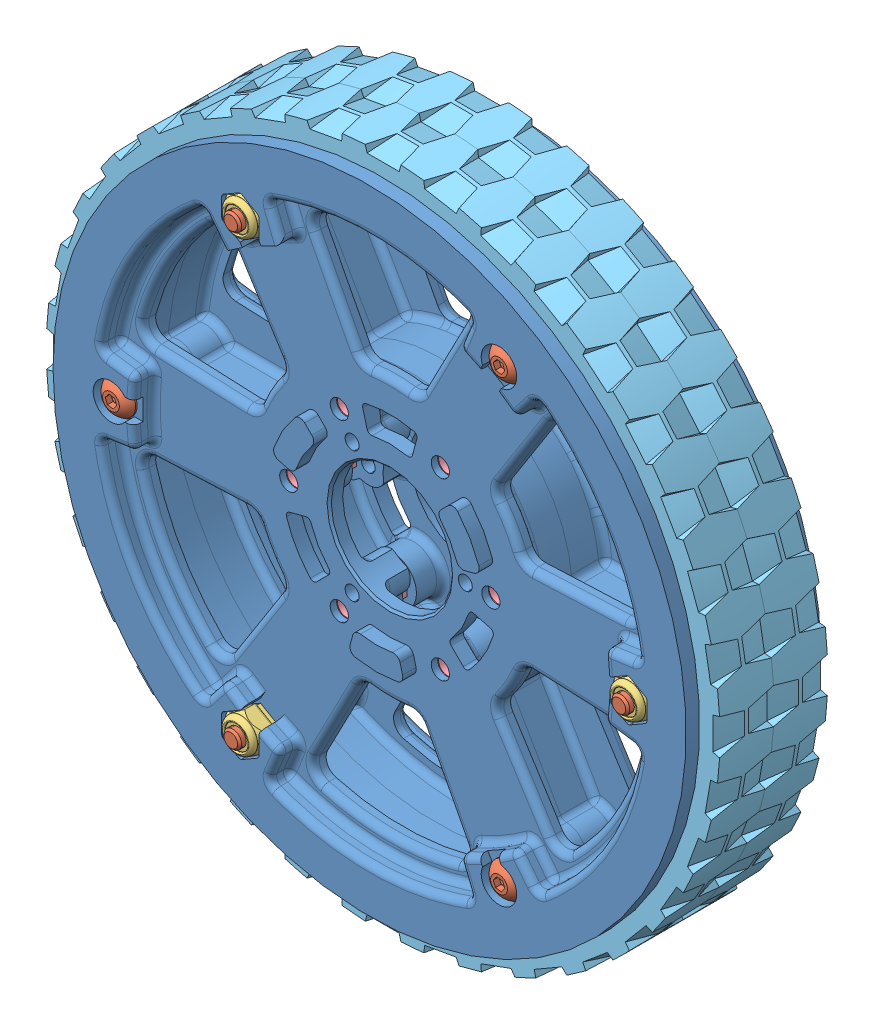
SolidWorks assembly 217-2589 1in.20121203, configuration Default. Lengths in mm.
Overall size (158.75 158.75 36.2).
22 component instances, 5 part files, 5 mates.
Components (placement in the parent):
- 217-2589-001 Rev3-1: 217-2589-001 Rev3 [Default] at origin size (149.22 149.22 19.81)
- 217-2589-001 Rev3-2: 217-2589-001 Rev3 [Default] x (-1 0 0) z (0 0 -1) size (149.22 149.22 19.81)
- SCREW-832-1250-1: SCREW-832-1250 [Default] at (60.96 0 -15.8623) x (0 0 1) z (-1 0 0) size (33.96 7.92 7.92)
- NUT-832-NYLOCK-1: NUT-832-NYLOCK [Default] at (60.96 0 12.0688) x (0.866025 0.5 0) z (0.5 -0.866025 0) size (10.2 5.86 8.12)
- BEAM-0750-1: BEAM-0750 [Default] at (11.9062 -20.6222 0.0635) x (0.866025 0.5 0) z (-0.5 0.866025 0) size (7.34 19.93 7.34)
- BEAM-0750-2: BEAM-0750 [Default] at (-11.9062 -20.6222 0.0635) x (0.866025 -0.5 0) z (0.5 0.866025 0) size (7.34 19.93 7.34)
- BEAM-0750-3: BEAM-0750 [Default] at (-23.8125 0 0.0635) x (0 -1 0) z (1 0 0) size (7.34 19.93 7.34)
- BEAM-0750-4: BEAM-0750 [Default] at (-11.9062 20.6222 0.0635) x (-0.866025 -0.5 0) z (0.5 -0.866025 0) size (7.34 19.93 7.34)
- BEAM-0750-5: BEAM-0750 [Default] at (11.9062 20.6222 0.0635) x (-0.866025 0.5 0) z (-0.5 -0.866025 0) size (7.34 19.93 7.34)
- BEAM-0750-6: BEAM-0750 [Default] at (23.8125 0 0.0635) x (0 1 0) z (-1 0 0) size (7.34 19.93 7.34)
- SCREW-832-1250-2: SCREW-832-1250 [Default] at (30.48 52.7929 15.8623) x (0 0 -1) z (0.923728 0.383049 0) size (33.96 7.92 7.92)
- NUT-832-NYLOCK-2: NUT-832-NYLOCK [Default] at (30.48 52.7929 -12.0688) x (-0.866025 -0.5 0) z (0.5 -0.866025 0) size (10.2 5.86 8.12)
- NUT-832-NYLOCK-3: NUT-832-NYLOCK [Default] at (30.48 -52.7929 -12.0688) x (0 1 0) z (-1 0 0) size (10.2 5.86 8.12)
- NUT-832-NYLOCK-4: NUT-832-NYLOCK [Default] at (-60.96 0 -12.0688) x (0.866025 -0.5 0) z (0.5 0.866025 0) size (10.2 5.86 8.12)
- SCREW-832-1250-3: SCREW-832-1250 [Default] at (-30.48 -52.7929 -15.8623) x (0 0 1) z (0.5 0.866025 0) size (33.96 7.92 7.92)
- SCREW-832-1250-4: SCREW-832-1250 [Default] at (-30.48 52.7929 -15.8623) x (0 0 1) z (0.5 -0.866025 0) size (33.96 7.92 7.92)
- NUT-832-NYLOCK-5: NUT-832-NYLOCK [Default] at (-30.48 -52.7929 12.0688) x (0 -1 0) z (-1 0 0) size (10.2 5.86 8.12)
- NUT-832-NYLOCK-6: NUT-832-NYLOCK [Default] at (-30.48 52.7929 12.0688) x (-0.866025 0.5 0) z (0.5 0.866025 0) size (10.2 5.86 8.12)
- SCREW-832-1250-5: SCREW-832-1250 [Default] at (30.48 -52.7929 15.8623) x (0 0 -1) z (-0.130134 -0.991496 0) size (33.96 7.92 7.92)
- SCREW-832-1250-6: SCREW-832-1250 [Default] at (-60.96 0 15.8623) x (0 0 -1) z (-0.793594 0.608447 0) size (33.96 7.92 7.92)
- 217-2860-001 Rev3-1: 217-2860-001 Rev3 [Default] at (0 0 -6.35) size (158.75 158.75 12.71)
- 217-2860-001 Rev3-2: 217-2860-001 Rev3 [Default] at (0 0 6.35) size (158.75 158.75 12.71)
Mates (geometry in assembly coordinates):
- Concentric1: concentric anti-aligned: cylinder of 217-2589-001 Rev3-1 through (0 0 -11.1125) axis (0 0 1) radius 74.6125; cylinder of 217-2860-001 Rev3-1 through (0 0 0) axis (0 0 -1) radius 79.375
- Concentric2: concentric aligned: cylinder of 217-2860-001 Rev3-1 through (0 0 0) axis (0 0 -1) radius 79.375; cylinder of 217-2860-001 Rev3-2 through (0 0 12.7) axis (0 0 -1) radius 79.375
- Coincident1: coincident anti-aligned: plane of 217-2860-001 Rev3-1 through (0 0 0) normal (0 0 1); plane of 217-2860-001 Rev3-2 through (0 0 0) normal (0 0 -1)
- Coincident3: coincident: point of 217-2860-001 Rev3-1; point of 217-2860-001 Rev3-2
- Coincident4: coincident aligned: plane of 217-2589-001 Rev3-1 through (0 0 -12.7) normal (0 0 -1); plane of 217-2860-001 Rev3-1 through (0 0 -12.7) normal (0 0 -1)
